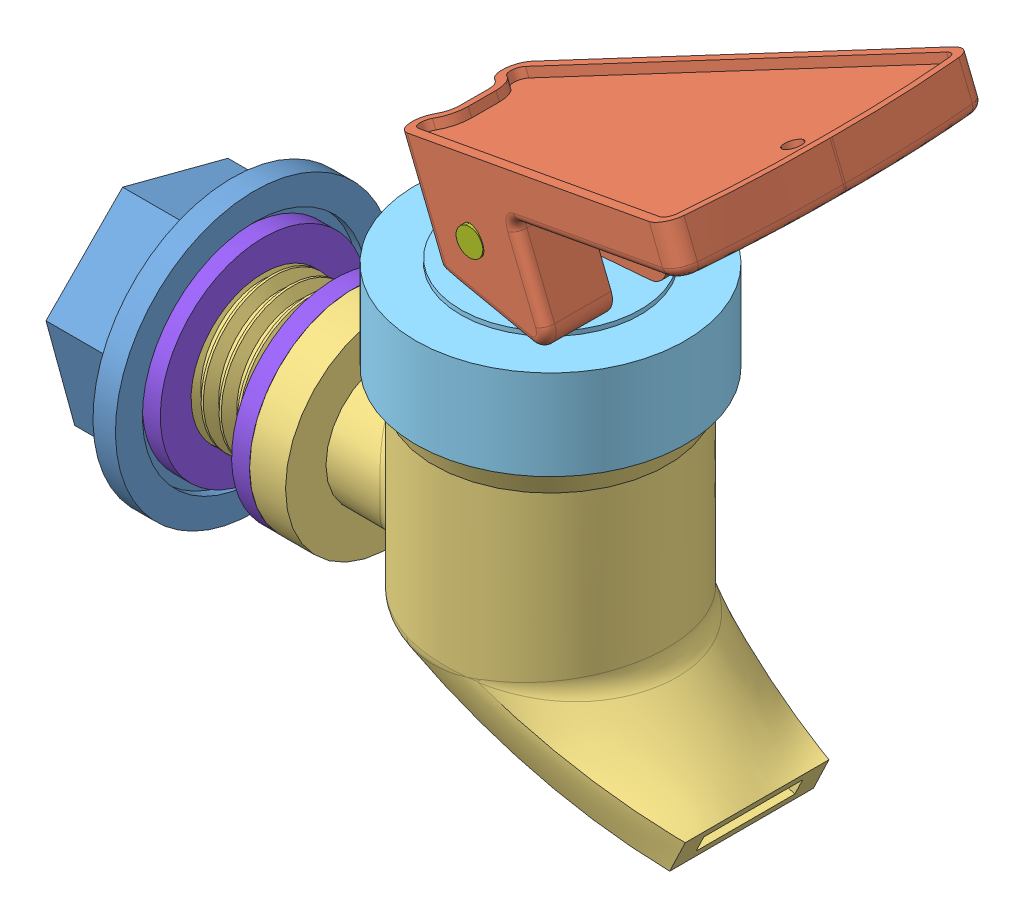
SolidWorks assembly tap model, configuration Default. Lengths in mm.
Overall size (81.89 71.83 41.34).
9 component instances, 8 part files, 16 mates.
Components (placement in the parent):
- Part1-1: Part1 [Default] at (-5.9655 -26.1876 33.711) x (1 0 0) z (0 -0.964592 -0.263748) size (11.5 31 31)
- Part2-1: Part2 [Default] at (-5.6311 -0.2582 33.6226) x (-0.002519 0 0.999997) z (0.927016 0.375013 0.002335) size (33.89 16.28 45.01)
- Part3-1: Part3 [Default] at (-8.5282 -26.1876 33.711) size (67.44 42.01 28)
- Part4-1: Part4 [Default] at (29.4718 -11.4376 33.711) x (0.002519 0 -0.999997) z (-0.999997 0 -0.002519) size (13.5 23.5 13.5)
- Part5-1: Part5 [Default] at (29.4718 -1.1876 33.711) x (-0.530387 0 -0.847756) z (-0.847756 0 0.530387) size (30 10.5 30)
- Part6-1: Part6 [Default] at (29.4718 -37.1876 33.711) x (0 1 0) z (0.002519 0 -0.999997) size (47 23 23)
- Part7-1: Part7 [Default] at (29.4945 5.3124 24.7117) x (0.020782 -0.999784 0.000052) z (-0.002519 0 0.999997) size (4.01 4.01 19.5)
- Part8-1: Part8 [Default] at (-4.4655 -26.1876 33.711) x (1 0 0) z (0 -0.083729 0.996489) size (2 23 23)
- Part8-2: Part8 [Default] at (5.4718 -26.1876 33.711) x (1 0 0) z (0 -0.585831 -0.810433) size (2 23 23)
Mates (geometry in assembly coordinates):
- Concentric1: concentric aligned: cylinder of Part3-1 through (-14.9655 -26.1876 33.711) axis (-1 0 0) radius 7; cylinder of Part8-2 through (7.4718 -26.1876 33.711) axis (-1 0 0) radius 8.0761
- Concentric2: concentric anti-aligned: cylinder of Part3-1 through (-14.9655 -26.1876 33.711) axis (-1 0 0) radius 7; circle of Part8-1
- Coincident1: coincident anti-aligned: plane of Part3-1 through (7.4718 -26.1876 33.711) normal (-1 0 0); plane of Part8-2 through (7.4718 -26.1876 33.711) normal (1 0 0)
- Concentric4: concentric anti-aligned: cylinder of Part1-1 through (-4.4655 -26.1876 33.711) axis (1 0 0) radius 12.5; cylinder of Part8-2 through (7.4718 -26.1876 33.711) axis (-1 0 0) radius 11.5
- Coincident3: coincident anti-aligned: plane of Part1-1 through (-4.4655 -26.1876 33.711) normal (1 0 0); plane of Part8-1 through (-4.4655 -26.1876 33.711) normal (-1 0 0)
- Coincident5: coincident aligned: plane of Part1-1 through (-14.9655 -26.1876 33.711) normal (-1 0 0); plane of Part3-1 through (-14.9655 -26.1876 33.711) normal (-1 0 0)
- Concentric5: concentric anti-aligned: cylinder of Part3-1 through (29.4718 -11.1876 33.711) axis (0 1 0) radius 7.5; cylinder of Part6-1 through (29.4718 -32.1876 33.711) axis (0 -1 0) radius 5.5
- Concentric6: concentric anti-aligned: cylinder of Part5-1 through (29.4718 -6.1876 33.711) axis (0 1 0) radius 2.5; cylinder of Part6-1 through (29.4718 9.8124 33.711) axis (0 -1 0) radius 2.25
- Coincident6: coincident aligned: plane of Part4-1 through (29.4718 -11.4376 33.711) normal (0.002519 0 -0.999997); plane of Part6-1 through (29.4718 -37.1876 33.711) normal (0.002519 0 -0.999997)
- Coincident7: coincident anti-aligned: plane of Part4-1 through (29.4718 -11.4376 33.711) normal (-0.999997 0 -0.002519); plane of Part6-1 through (29.4718 -37.1876 33.711) normal (0.999997 0 0.002519)
- Tangent8: tangent aligned: torus of Part4-1; plane of Part6-1 through (29.4718 -11.1876 33.711) normal (0 1 0)
- Coincident14: coincident anti-aligned: plane of Part5-1 through (29.4718 -11.1876 33.711) normal (0 -1 0); plane of Part6-1 through (29.4718 -11.1876 33.711) normal (0 1 0)
- Coincident15: coincident anti-aligned: plane of Part3-1 through (15.4718 -11.1876 33.711) normal (0 1 0); plane of Part5-1 through (29.4718 -11.1876 33.711) normal (0 -1 0)
- Concentric8: concentric anti-aligned: cylinder of Part2-1 through (29.5145 5.3124 16.7667) axis (-0.002519 0 0.999997) radius 1.5; cylinder of Part6-1 through (29.4428 5.3124 45.211) axis (0.002519 0 -0.999997) radius 1.5
- Concentric9: concentric anti-aligned: cylinder of Part2-1 through (29.5145 5.3124 16.7667) axis (-0.002519 0 0.999997) radius 1.5; cylinder of Part7-1 through (29.4491 5.3124 42.7117) axis (0.002519 0 -0.999997) radius 1.5
- Coincident22: coincident anti-aligned: plane of Part6-1 through (29.4718 -37.1876 33.711) normal (0.002519 0 -0.999997)
